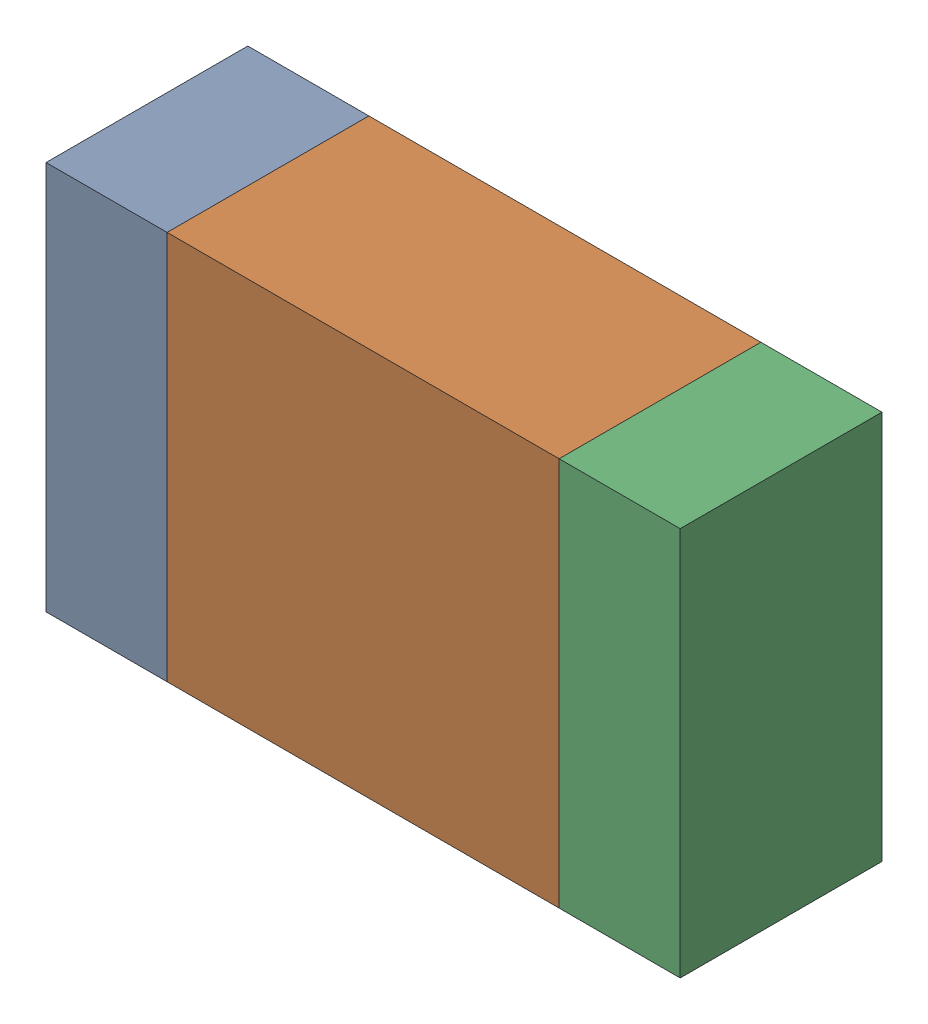
SolidWorks assembly R13-2, configuration Default. Lengths in mm.
Overall size (2.2 1.35 0.7).
6 component instances, 2 part files, 0 mates.
Components (placement in the parent):
- 959209344-2-1: 959209344-2 [Default] at (105.4089 93.8529 0) size (0.42 1.35 0.7)
  - Extruded-87-1: Extruded-87 [Default] at origin size (0.42 1.35 0.7)
- 959209480-2-1: 959209480-2 [Default] at (106.2989 93.8529 0) size (1.36 1.35 0.7)
  - Extruded-88-1: Extruded-88 [Default] at origin size (1.36 1.35 0.7)
- 959209344-2-2: 959209344-2 [Default] at (107.1889 93.8529 0) size (0.42 1.35 0.7)
  - Extruded-87-1: Extruded-87 [Default] at origin size (0.42 1.35 0.7)
